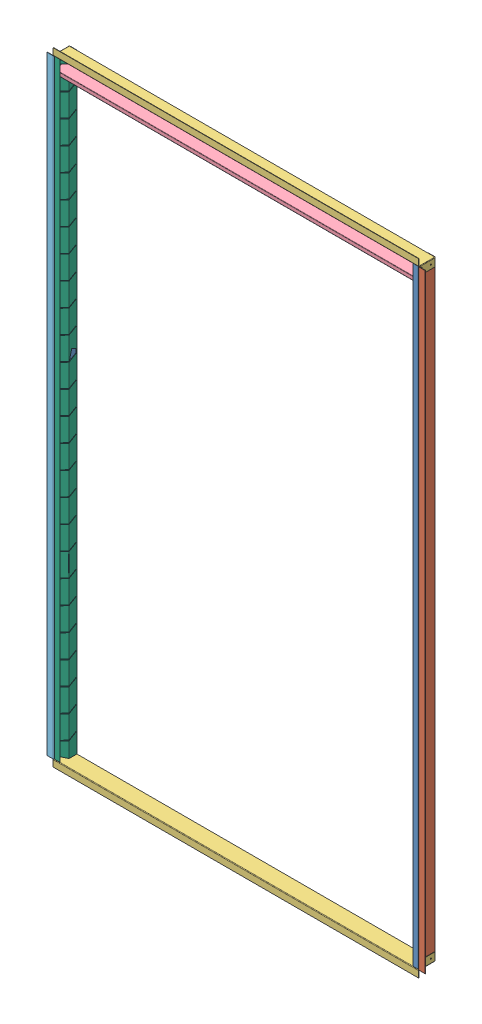
SolidWorks assembly louvers_asm (1), configuration Default. Lengths in mm.
Overall size (1373.48 2260.6 61.3).
8 component instances, 6 part files, 0 mates.
Components (placement in the parent):
- louvers_asm (1).STEP-1: louvers_asm (1).STEP [Default] at origin size (1373.48 2260.6 61.3)
  - PRT_0015-M_Ex_Split_Carriage.STEP-1: PRT_0015-M_Ex_Split_Carriage.STEP [Default] at (-700.5742 -0.8227 -3.4126) size (1322.88 2210 58.36)
  - PRT_0016-M_Ex_Louver_Frame.STEP-1: PRT_0016-M_Ex_Louver_Frame.STEP [Default] at (-699.9742 -0.8227 -3.5126) size (49 2210 61.3)
  - PRT_0017-M_Ex_Louver_Frame_Beam.STEP-1: PRT_0017-M_Ex_Louver_Frame_Beam.STEP [Default] at (-699.6742 -0.5227 -2.776) size (1329 54 58.83)
  - PRT_0017-M_Ex_Louver_Frame_Beam.STEP-2: PRT_0017-M_Ex_Louver_Frame_Beam.STEP [Default] at (-702.3945 1.573 -2.776) x (-1 0 0) z (0 0 1) size (1329 54 58.83)
  - PRT_0014-M_Ex_Louver_Split.STEP-1: PRT_0014-M_Ex_Louver_Split.STEP [Default] at (-693.1742 -1.4 -2.4126) size (1308 43.54 52.03)
  - PRT_0020-M_Ex_Louver_Frame-2.STEP-1: PRT_0020-M_Ex_Louver_Frame-2.STEP [Default] at (-701.1742 1.873 -3.5126) x (-1 0 0) z (0 0 1) size (49 2210 61.3)
  - PRT_0019-M_Ex_Split_2.STEP-1: PRT_0019-M_Ex_Split_2.STEP [Default] at (-700.5742 -0.8227 -3.4126) size (25.3 2210 58.36)
